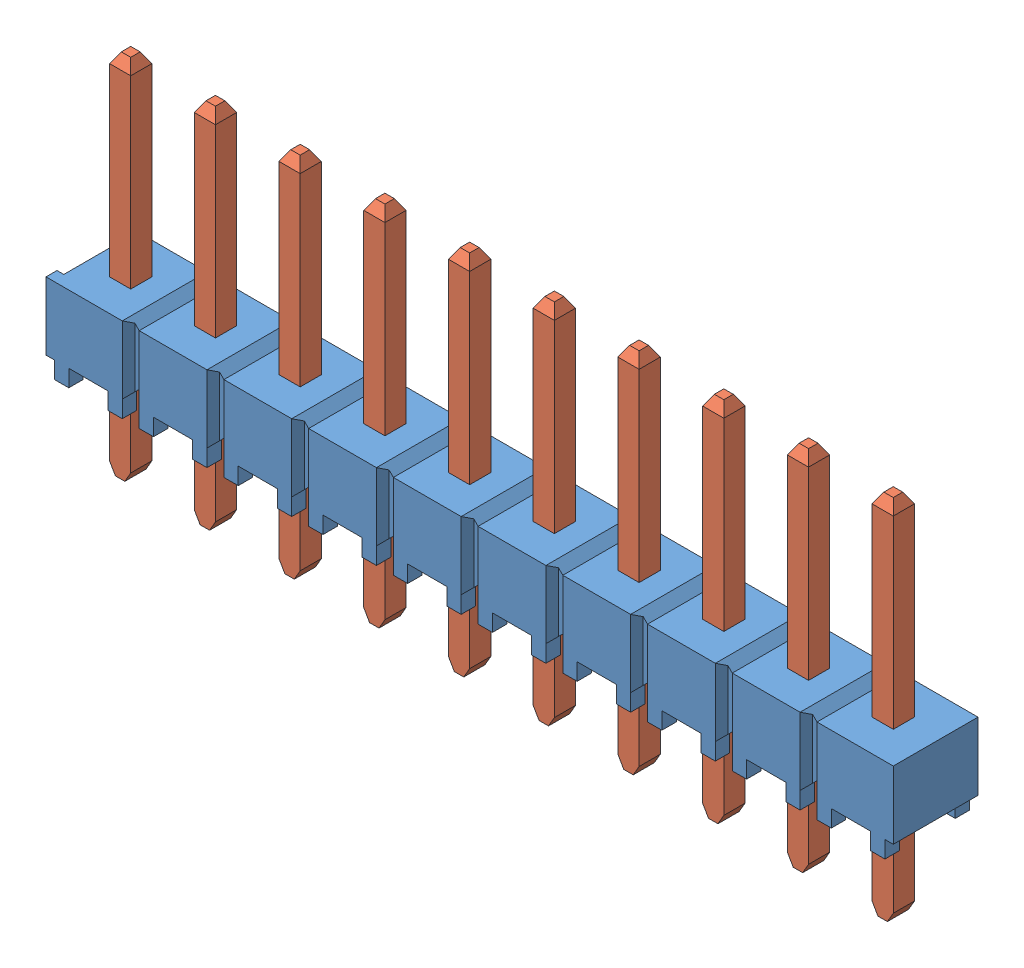
SolidWorks assembly TSW_110_07_G_S, configuration Default. Lengths in mm.
Overall size (25.53 10.92 2.54).
2 component instances, 2 part files, 0 mates.
Components (placement in the parent):
- _TSW_110_07_G_S_body_2-1: _TSW_110_07_G_S_body_2 [Default] at origin size (25.53 2.54 2.54)
- _T_1S6_07_TSW_1_07_10_S_4-1: _T_1S6_07_TSW_1_07_10_S_4 [Default] at (0 -2.54 0) size (23.75 10.92 0.89)
